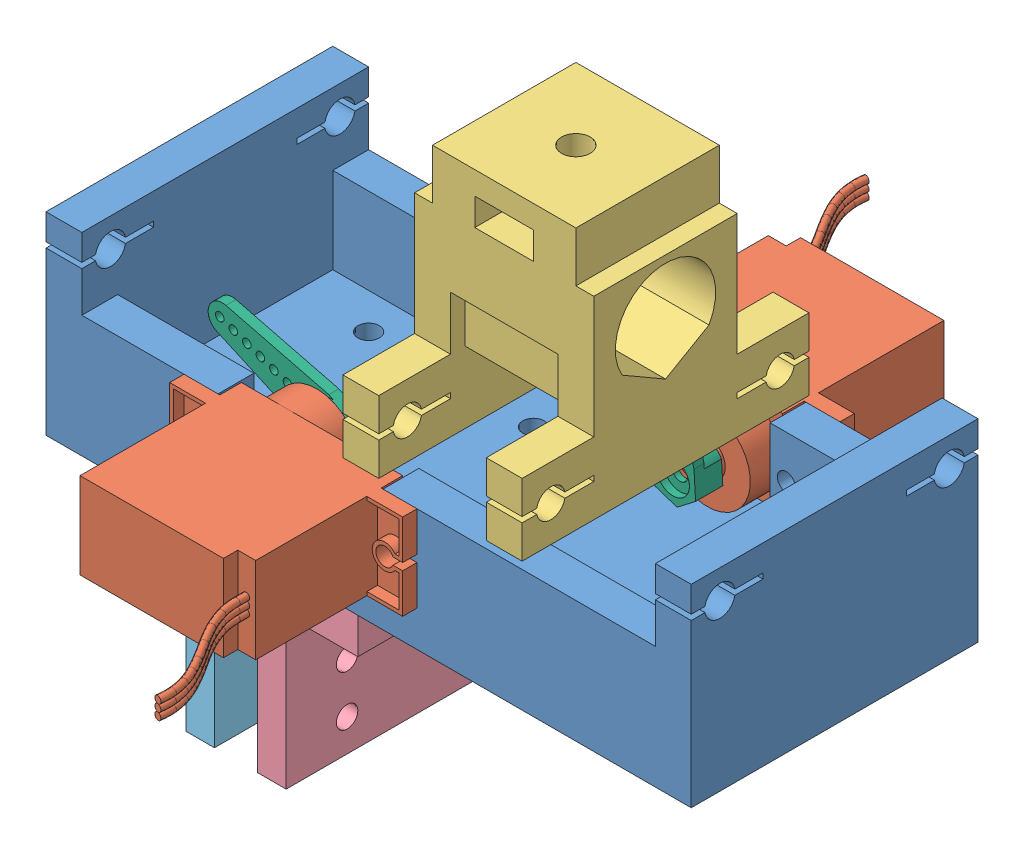
SolidWorks assembly Assem-End-Effectr, configuration Default. Lengths in mm.
Overall size (90 78 112.4).
8 component instances, 6 part files, 18 mates.
Components (placement in the parent):
- Servo Housing-1: Servo Housing [Default] at origin size (90 27 40)
- Servo Motor SG90 1PC.stp-1: Servo Motor SG90 1PC.stp [Default] at (-9.5 11 39.5) x (0 1 0) z (0 0 -1) size (12 33.08 46.7)
- Pen Holder-1: Pen Holder [Default] at (8.9138 28 0) x (0 0 1) z (-1 0 0) size (40 34 25)
- Mount Servo Housing-1: Mount Servo Housing [Default] at (-26.5 -22 0) x (1 0 0) z (0 1 0) size (14 40 26)
- Mount Servo Housing Bottom-1: Mount Servo Housing Bottom [Default] at (-10.5 -22 0) x (-1 0 0) z (0 1 0) size (14 40 26)
- Servo Motor SG90 1PC.stp-2: Servo Motor SG90 1PC.stp [Default] at (9.5 11 -39.5) x (0 1 0) z (0 0 1) size (12 33.08 46.7)
- SG90 - Micro Servo 9g - Tower Pro.4-1: SG90 - Micro Servo 9g - Tower Pro.4 [Peça] at (14.75 11 -7.7) x (-0.16589 0.986144 0) z (0.986144 0.16589 0) size (34.5 3.8 16.7)
- SG90 - Micro Servo 9g - Tower Pro.4-2: SG90 - Micro Servo 9g - Tower Pro.4 [Peça] at (-14.75 11 8.7) x (-0.944518 0.32846 0) z (-0.32846 -0.944518 0) size (34.5 3.8 16.7)
Mates (geometry in assembly coordinates):
- Coincident2: coincident anti-aligned: plane of Servo Housing-1 through (-45 5 20) normal (0 0 1); plane of Servo Motor SG90 1PC.stp-1 through (-9.5 11 20) normal (0 0 -1)
- Concentric15: concentric aligned: cylinder of Servo Housing-1 through (45 23 16) axis (-1 0 0) radius 2.125; cylinder of Pen Holder-1 through (21.4138 23 16) axis (-1 0 0) radius 2
- Concentric16: concentric aligned: cylinder of Servo Housing-1 through (45 23 -16) axis (-1 0 0) radius 2.125; cylinder of Pen Holder-1 through (21.4138 23 -16) axis (-1 0 0) radius 2
- Coincident23: coincident anti-aligned: plane of Servo Housing-1 through (0 0 0) normal (0 -1 0); plane of Mount Servo Housing-1 through (-26.5 0 0) normal (0 1 0)
- Concentric17: concentric aligned: cylinder of Servo Housing-1 through (-7 27 -10) axis (0 -1 0) radius 1.5; cylinder of Mount Servo Housing-1 through (-7 -2 -10) axis (0 -1 0) radius 1.5
- Concentric18: concentric aligned: cylinder of Servo Housing-1 through (-7 27 10) axis (0 -1 0) radius 1.5; cylinder of Mount Servo Housing-1 through (-7 -2 10) axis (0 -1 0) radius 1.5
- Coincident24: coincident anti-aligned: plane of Servo Housing-1 through (0 0 0) normal (0 -1 0); plane of Mount Servo Housing Bottom-1 through (-10.5 0 0) normal (0 1 0)
- Concentric19: concentric aligned: cylinder of Servo Housing-1 through (-30 27 -10) axis (0 -1 0) radius 1.5; cylinder of Mount Servo Housing Bottom-1 through (-30 -2 -10) axis (0 -1 0) radius 1.5
- Concentric20: concentric aligned: cylinder of Servo Housing-1 through (-30 27 10) axis (0 -1 0) radius 1.5; cylinder of Mount Servo Housing Bottom-1 through (-30 -2 10) axis (0 -1 0) radius 1.5
- Coincident25: coincident anti-aligned: plane of Servo Housing-1 through (-45 5 -20) normal (0 0 -1); plane of Servo Motor SG90 1PC.stp-2 through (9.5 11 -20) normal (0 0 1)
- Coincident26: coincident anti-aligned: plane of Servo Motor SG90 1PC.stp-2 through (14.75 11 -9.5) normal (0 0 1); plane of SG90 - Micro Servo 9g - Tower Pro.4-1 through (14.75 11 -9.5) normal (0 0 -1)
- Concentric23: concentric anti-aligned: cylinder of Servo Motor SG90 1PC.stp-2 through (14.75 11 -12.5) axis (0 0 -1) radius 6; cylinder of SG90 - Micro Servo 9g - Tower Pro.4-1 through (14.75 11 -9.1) axis (0 0 1) radius 3.45
- Concentric24: concentric anti-aligned: cylinder of Servo Motor SG90 1PC.stp-1 through (-14.75 11 9.5) axis (0 0 1) radius 2.5; cylinder of SG90 - Micro Servo 9g - Tower Pro.4-2 through (-14.75 11 10.1) axis (0 0 -1) radius 3.45
- Coincident27: coincident anti-aligned: plane of Servo Motor SG90 1PC.stp-1 through (-11.5 11 12.5) normal (0 0 -1); plane of SG90 - Micro Servo 9g - Tower Pro.4-2 through (-14.75 11 12.5) normal (0 0 1)
- Concentric29: concentric aligned: cylinder of Servo Housing-1 through (23.25 11 -23.5355) axis (0 0 1) radius 1.25; cylinder of Servo Motor SG90 1PC.stp-2 through (23.25 11 -25) axis (0 0 1) radius 1.25
- Concentric30: concentric aligned: cylinder of Servo Housing-1 through (-4.25 11 -23.5355) axis (0 0 1) radius 1.25; cylinder of Servo Motor SG90 1PC.stp-2 through (-4.25 11 -25) axis (0 0 1) radius 1.25
- Concentric36: concentric anti-aligned: cylinder of Servo Housing-1 through (-23.25 11 11.4645) axis (0 0 1) radius 1.25; cylinder of Servo Motor SG90 1PC.stp-1 through (-23.25 11 25) axis (0 0 -1) radius 1.25
- Concentric37: concentric anti-aligned: cylinder of Servo Motor SG90 1PC.stp-1 through (4.25 11 25) axis (0 0 -1) radius 1.25; cylinder of Servo Housing-1 through (4.25 11 11.4645) axis (0 0 1) radius 1.25
